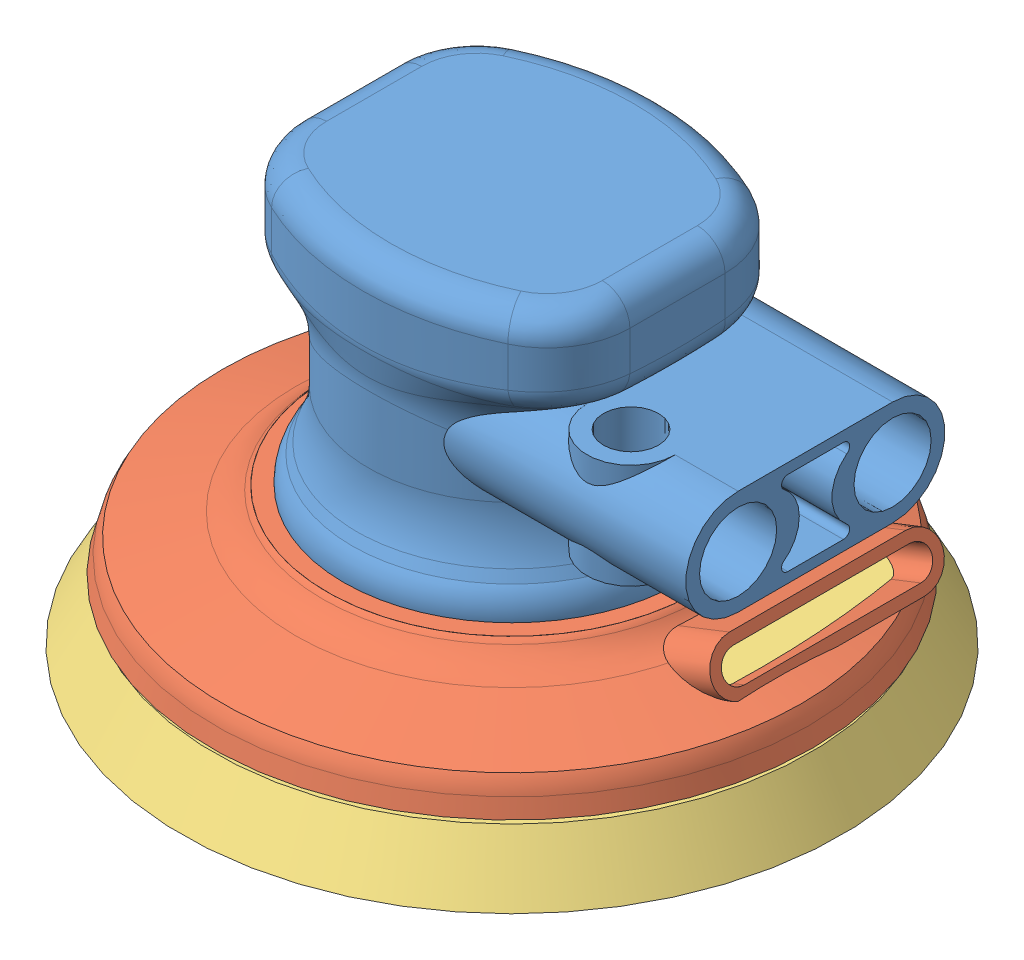
SolidWorks assembly Sander Complete - SANDER ONLY, configuration Default. Lengths in mm.
Overall size (190.84 93.98 190.84).
3 component instances, 3 part files, 5 mates.
Components (placement in the parent):
- Body-1: Body [Default] at (13.4462 60.7349 53.9104) size (108.61 72.39 77.53)
- Vacuum Shield-1: Vacuum Shield [Default] at (13.4462 8.6649 53.9104) x (0 0 1) z (-1 0 0) size (138.47 21.53 138.47)
- Sanding Disk-1: Sanding Disk [Default] at (13.4462 -2.7651 53.9104) x (0.304446 0 0.95253) z (0 -1 0) size (151.82 151.82 22.86)
Mates (geometry in assembly coordinates):
- Coincident1: coincident aligned: cylinder of Body-1 through (13.4462 6.1249 53.9104) axis (0 1 0) radius 37.465; circle of Vacuum Shield-1
- Concentric1: concentric anti-aligned: circle of Body-1; circle of Sanding Disk-1
- Parallel1: parallel aligned: line of Body-1 through (83.2962 58.9569 36.1304) axis (0 0 1); line of Vacuum Shield-1 through (69.8613 18.4273 19.6204) axis (0 0 1)
- Lock1: lock: unknown of Body-1; unknown of Vacuum Shield-1
- Lock5: lock: unknown of Sanding Disk-1; unknown of Body-1
